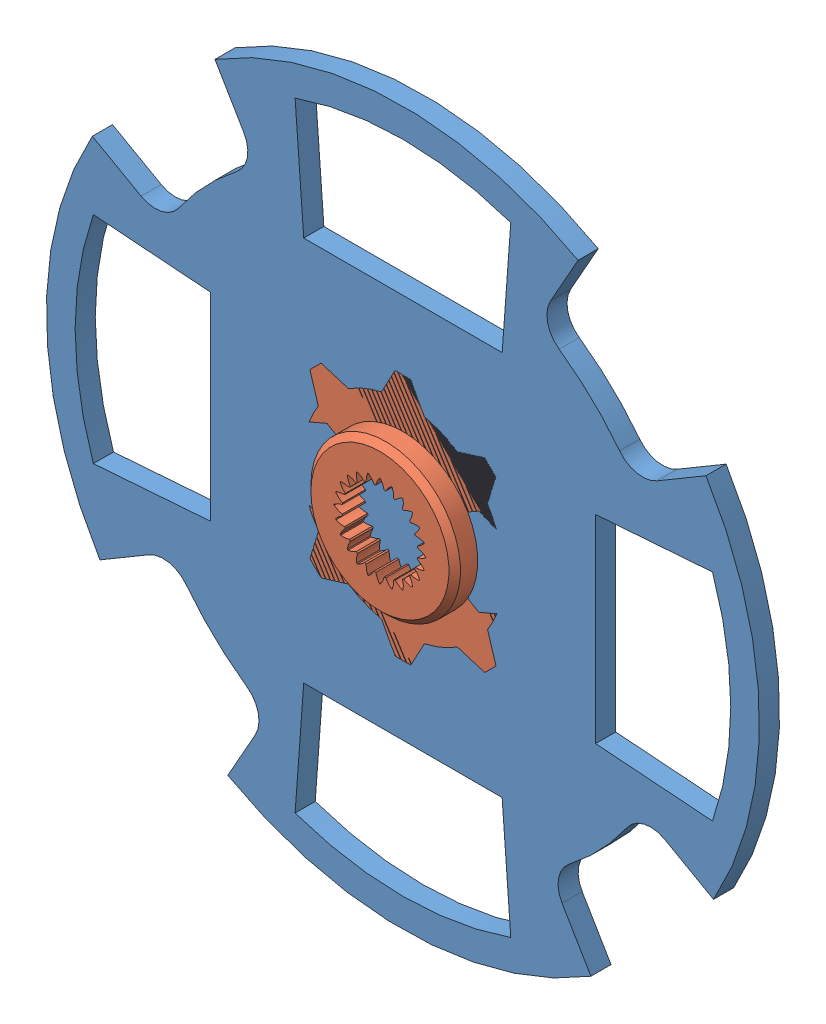
SolidWorks assembly Assem1, configuration Default. Lengths in mm.
Overall size (124 124 20).
2 component instances, 2 part files, 3 mates.
Components (placement in the parent):
- 6-2: 6 [Default] at origin size (124 124 3.5)
- 5-2: 5 [Default] at (0 0 -14.25) x (0 0 1) z (-1 0 0) size (20 43 32.68)
Mates (geometry in assembly coordinates):
- Coincident4: coincident: point of 6-2
- Coincident8: coincident aligned: plane of 6-2 through (0 0 1.75) normal (0 0 1); plane of 5-2 through (0 0 1.75) normal (0 0 1)
- Concentric3: concentric aligned: circle of 6-2; circle of 5-2
